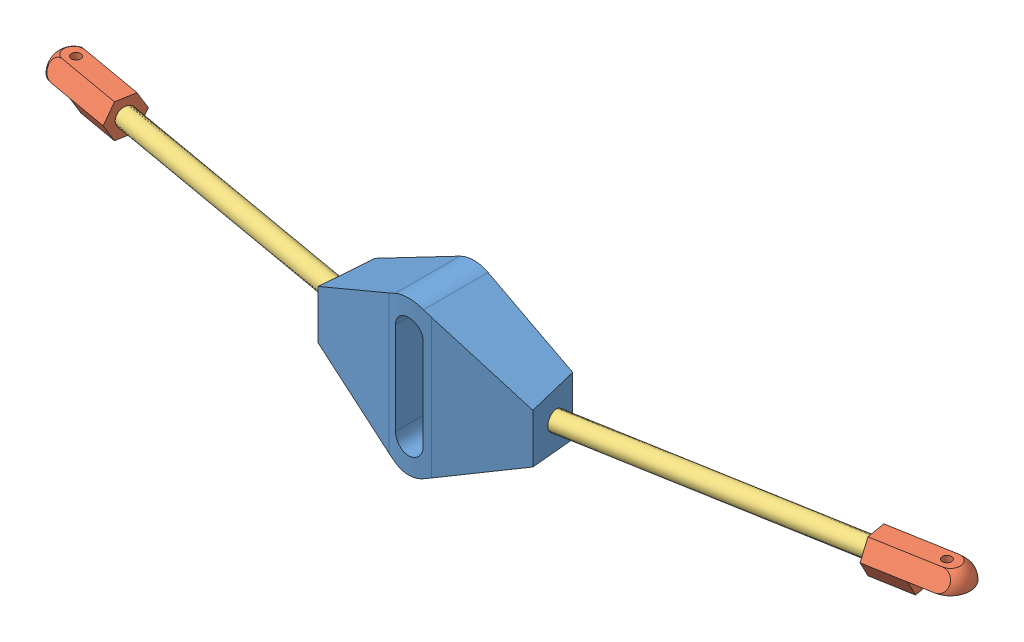
SolidWorks assembly Lenkstange, configuration Standard. Lengths in mm.
Overall size (150.34 25 20.55).
5 component instances, 3 part files, 12 mates.
Components (placement in the parent):
- Lenkstange-Mittelstück-1: Lenkstange-Mittelstück [Standard] at origin size (35 25 10.66)
- Gelenkbolzen-1: Gelenkbolzen [M3] at (-61.1519 0 -4.388) x (0 1 0) z (0.984808 0 0.173648) size (5.5 6.35 13.68)
- Gewindestange-1: Gewindestange [M3x60] at (-37.5165 0 -0.2204) x (-0.173648 0 0.984808) z (-0.984808 0 -0.173648) size (3 3 60)
- Gewindestange-3: Gewindestange [M3x60] at (37.5165 0 -0.2204) x (-0.173648 0 -0.984808) z (-0.984808 0 0.173648) size (3 3 60)
- Gelenkbolzen-5: Gelenkbolzen [M3] at (61.1519 0 -4.388) x (0 1 0) z (-0.984808 0 0.173648) size (5.5 6.35 13.68)
Mates (geometry in assembly coordinates):
- Konzentrisch1: concentric aligned: cylinder of Gelenkbolzen-1 through (-67.0608 0 -5.4299) axis (0.984808 0 0.173648) radius 1.23; cylinder of Gewindestange-1 through (-67.0608 0 -5.4299) axis (0.984808 0 0.173648) radius 1.5
- Deckungsgleich2: coincident anti-aligned: plane of Gelenkbolzen-1 through (-67.0608 0 -5.4299) normal (0.984808 0 0.173648); plane of Gewindestange-1 through (-67.0608 0 -5.4299) normal (-0.984808 0 -0.173648)
- Deckungsgleich4: coincident aligned: plane of Lenkstange-Mittelstück-1 through (0 0 0) normal (0 1 0); plane of assembly through (0 0 0) normal (0 1 0)
- Deckungsgleich5: coincident aligned: plane of Lenkstange-Mittelstück-1 through (0 0 0) normal (0 0 1); plane of assembly through (0 0 0) normal (0 0 1)
- Konzentrisch2: concentric anti-aligned: cylinder of Lenkstange-Mittelstück-1 through (-4.9009 0 5.5306) axis (-0.984808 0 -0.173648) radius 1.23; cylinder of Gewindestange-1 through (-67.0608 0 -5.4299) axis (0.984808 0 0.173648) radius 1.5
- Deckungsgleich6: coincident aligned: plane of Gelenkbolzen-1; plane of assembly through (0 0 0) normal (0 1 0)
- Abstand1: distance = 71 mm: line of Gelenkbolzen-1 through (-71 0 -6.1245) axis (0 1 0); plane of assembly
- Deckungsgleich8: coincident aligned: plane of Gewindestange-1; plane of assembly through (0 0 0) normal (0 1 0)
- Konzentrisch3: concentric anti-aligned: cylinder of Gewindestange-3 through (7.9723 0 4.989) axis (0.984808 0 -0.173648) radius 1.5; cylinder of Gelenkbolzen-5 through (67.0608 0 -5.4299) axis (-0.984808 0 0.173648) radius 1.23
- Deckungsgleich9: coincident anti-aligned: plane of Gewindestange-3 through (67.0608 0 -5.4299) normal (0.984808 0 -0.173648); plane of Gelenkbolzen-5 through (67.0608 0 -5.4299) normal (-0.984808 0 0.173648)
- Symmetrisch1: symmetric aligned: plane of Lenkstange-Mittelstück-1 through (0 0 0) normal (1 0 0); plane of Gewindestange-1 through (-7.9723 0 4.989) normal (0.984808 0 0.173648); plane of Gewindestange-3 through (7.9723 0 4.989) normal (-0.984808 0 0.173648)
- Deckungsgleich10: coincident anti-aligned: plane of Gewindestange-3; plane of assembly through (0 0 0) normal (0 1 0)
